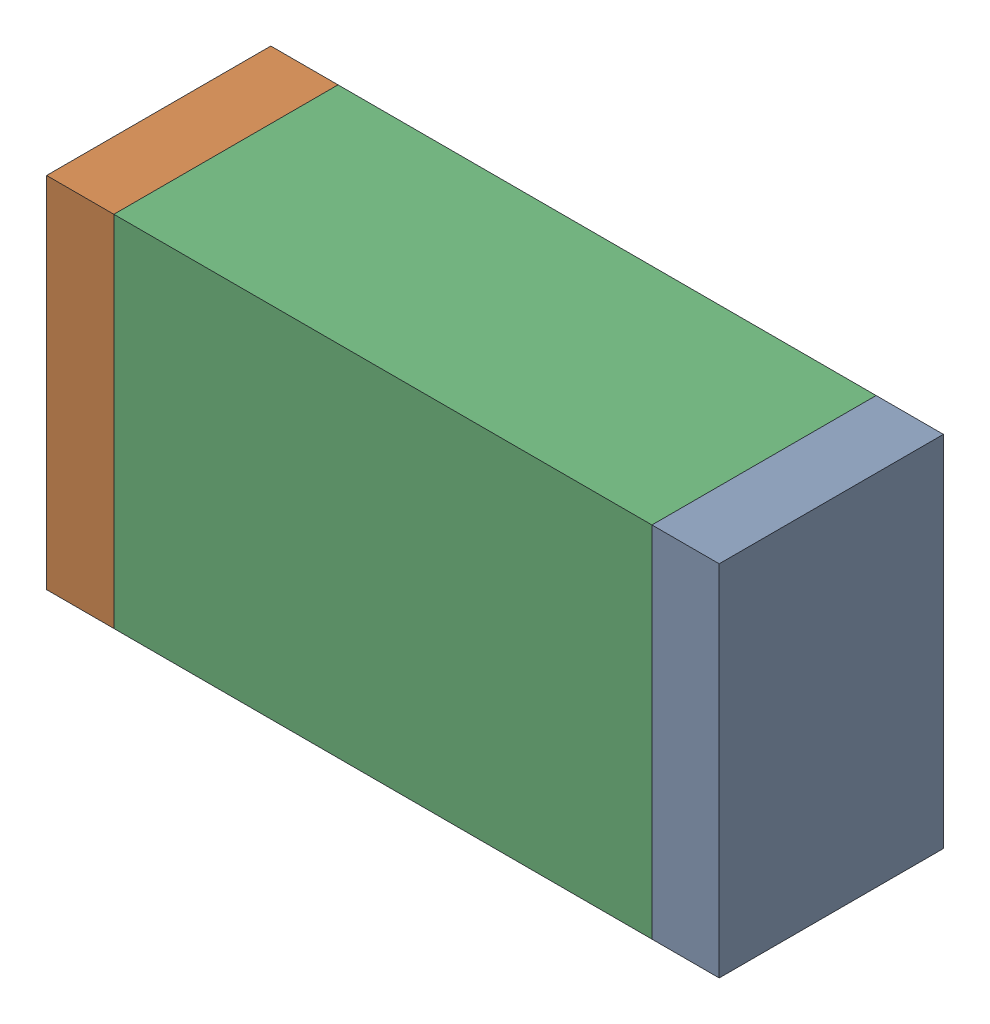
SolidWorks assembly R62, configuration Default. Lengths in mm.
Overall size (1.5 0.8 0.5).
6 component instances, 2 part files, 0 mates.
Components (placement in the parent):
- 836752496-1: 836752496 [Default] at (116.375 72.75 0) size (0.15 0.8 0.5)
  - Extruded_2-1: Extruded_2 [Default] at origin size (0.15 0.8 0.5)
- 836752496-2: 836752496 [Default] at (115.025 72.75 0) size (0.15 0.8 0.5)
  - Extruded_2-1: Extruded_2 [Default] at origin size (0.15 0.8 0.5)
- 836752368-1: 836752368 [Default] at (115.7 72.75 0) size (1.2 0.8 0.5)
  - Extruded-1: Extruded [Default] at origin size (1.2 0.8 0.5)
